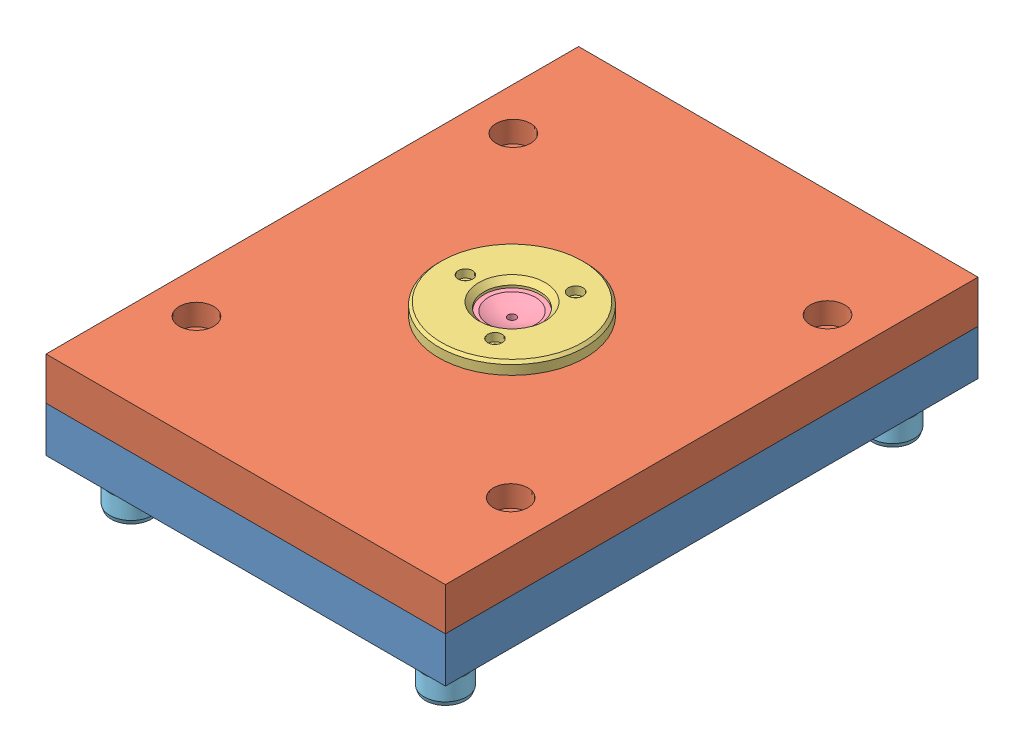
SolidWorks assembly Porta molde 300x400 Parte Superior, configuration Valor predeterminado. Lengths in mm.
Overall size (300 109 400).
20 component instances, 6 part files, 15 mates.
Components (placement in the parent):
- Placa cavidade P1-1: Placa cavidade P1 [Valor predeterminado] at (12.8367 308.101 0) x (-1 0 0) z (0 0 1) size (300 34 400)
- Placa base superior-1: Placa base superior [Valor predeterminado] at (12.8367 340.101 0) x (-1 0 0) z (0 0 1) size (300 32 400)
- Anel de centragem-1: Anel de centragem [Valor predeterminado] at (12.8367 337.101 0) x (0.5 0 0.866025) z (-0.866025 0 0.5) size (110 12 110)
- Socket Head Cap Screw_ISO-3: Socket Head Cap Screw_ISO [ISO 4762 M6 x 25 --- 25N] at (30.3367 349.101 -30.3109) x (0 -1 0) z (0.216767 0 0.976223) (suppressed, hidden)
- Socket Head Cap Screw_ISO-4: Socket Head Cap Screw_ISO [ISO 4762 M6 x 25 --- 25N] at (-22.1633 349.101 0) x (0 -1 0) z (0.737051 0 -0.675837) (suppressed, hidden)
- Socket Head Cap Screw_ISO-5: Socket Head Cap Screw_ISO [ISO 4762 M6 x 25 --- 25N] at (30.3367 349.101 30.3109) x (0 -1 0) z (-0.953818 0 -0.300386) (suppressed, hidden)
- Bico-1: Bico [Valor predeterminado] at (12.8367 274.101 0) size (48 69 48)
- Socket Head Cap Screw_ISO-6: Socket Head Cap Screw_ISO [ISO 4762 M16 x 30 --- 30N] at (130.8367 340.101 -119) x (0 -1 0) z (0 0 1) (suppressed, hidden)
- Socket Head Cap Screw_ISO-7: Socket Head Cap Screw_ISO [ISO 4762 M16 x 30 --- 30N] at (130.8367 340.101 119) x (0 -1 0) z (0 0 1) (suppressed, hidden)
- Socket Head Cap Screw_ISO-8: Socket Head Cap Screw_ISO [ISO 4762 M16 x 30 --- 30N] at (-105.1633 340.101 -119) x (0 -1 0) z (0 0 1) (suppressed, hidden)
- Socket Head Cap Screw_ISO-9: Socket Head Cap Screw_ISO [ISO 4762 M16 x 30 --- 30N] at (-105.1633 340.101 119) x (0 -1 0) z (0 0 1) (suppressed, hidden)
- Socket Head Cap Screw_ISO-10: Socket Head Cap Screw_ISO [ISO 4762 M16 x 150 --- 44N] at (130.8367 -5.899 -119) x (0 1 0) z (0 0 1) (suppressed, hidden)
- Socket Head Cap Screw_ISO-11: Socket Head Cap Screw_ISO [ISO 4762 M16 x 150 --- 44N] at (130.8367 -5.899 119) x (0 1 0) z (0 0 1) (suppressed, hidden)
- Socket Head Cap Screw_ISO-12: Socket Head Cap Screw_ISO [ISO 4762 M16 x 150 --- 44N] at (-105.1633 -5.899 -119) x (0 1 0) z (0 0 1) (suppressed, hidden)
- Socket Head Cap Screw_ISO-13: Socket Head Cap Screw_ISO [ISO 4762 M16 x 150 --- 44N] at (-105.1633 -5.899 119) x (0 1 0) z (0 0 1) (suppressed, hidden)
- Pino-1: Pino [C46] at (130.8367 308.101 168) x (0 -1 0) z (0.180366 0 0.9836) size (68 48 48)
- Pino-2: Pino [C46] at (130.8367 308.101 -168) x (0 -1 0) z (0.180366 0 0.9836) size (68 48 48)
- Pino-3: Pino [C46] at (-105.1633 308.101 168) x (0 -1 0) z (0.180366 0 0.9836) size (68 48 48)
- Pino-4: Pino [C46] at (-105.1633 308.101 -168) x (0 -1 0) z (0.180366 0 0.9836) size (68 48 48)
- Socket Head Cap Screw_ISO-14: Socket Head Cap Screw_ISO [ISO 4762 M8 x 25 --- 25N] at (-71.1633 31.101 188) x (0 1 0) z (0 0 1) (suppressed, hidden)
Mates (geometry in assembly coordinates):
- Coincidente17: coincident anti-aligned: plane of Placa cavidade P1-1 through (162.8367 308.101 200) normal (0 1 0); plane of Placa base superior-1 through (162.8367 308.101 200) normal (0 -1 0)
- Coincidente18: coincident aligned: plane of Placa cavidade P1-1 through (162.8367 274.101 -200) normal (1 0 0); plane of Placa base superior-1 through (162.8367 308.101 -200) normal (1 0 0)
- Coincidente19: coincident aligned: plane of Placa cavidade P1-1 through (162.8367 274.101 200) normal (0 0 1); plane of Placa base superior-1 through (162.8367 308.101 200) normal (0 0 1)
- Coincidente26: coincident anti-aligned: plane of Placa base superior-1 through (12.8367 337.101 0) normal (0 1 0); plane of Anel de centragem-1 through (31.8367 337.101 32.909) normal (0 -1 0)
- Coincidente27: coincident anti-aligned: circle of Placa base superior-1; cylinder of Anel de centragem-1 through (12.8367 337.101 0) axis (0 -1 0) radius 45
- Concêntrico1: concentric aligned: cylinder of Placa base superior-1 through (30.3367 337.101 -30.3109) axis (0 1 0) radius 2.5; cylinder of Anel de centragem-1 through (30.3367 349.101 -30.3109) axis (0 1 0) radius 3.3
- Concêntrico2: concentric aligned: cylinder of Anel de centragem-1; cylinder of Socket Head Cap Screw_ISO-3
- Coincidente37: coincident anti-aligned: plane of Anel de centragem-1; plane of Socket Head Cap Screw_ISO-3
- Coincidente38: coincident anti-aligned: plane of Placa cavidade P1-1 through (162.8367 308.101 200) normal (0 1 0); plane of Bico-1 through (24.8367 308.101 0) normal (0 -1 0)
- Concêntrico3: concentric anti-aligned: cylinder of Placa cavidade P1-1 through (12.8367 274.101 0) axis (0 1 0) radius 13; cylinder of Bico-1 through (12.8367 274.101 0) axis (0 -1 0) radius 13
- Coincidente39: coincident anti-aligned: plane of Placa base superior-1; plane of Socket Head Cap Screw_ISO-6
- Concêntrico4: concentric aligned: cylinder of Placa base superior-1; cylinder of Socket Head Cap Screw_ISO-6
- Coincidente44: coincident anti-aligned: plane of Placa cavidade P1-1 through (109.8367 300.101 168) normal (0 1 0); plane of Pino-1 through (151.4923 300.101 164.2123) normal (0 -1 0)
- Concêntrico9: concentric anti-aligned: cylinder of Placa cavidade P1-1 through (130.8367 308.101 168) axis (0 1 0) radius 21; cylinder of Pino-1 through (130.8367 104.8026 168) axis (0 -1 0) radius 21
- LocalLPattern2: unknown: line of Placa cavidade P1-1 through (162.8367 274.101 200) axis (-1 0 0); line of Placa cavidade P1-1 through (162.8367 274.101 -200) axis (0 0 1)
